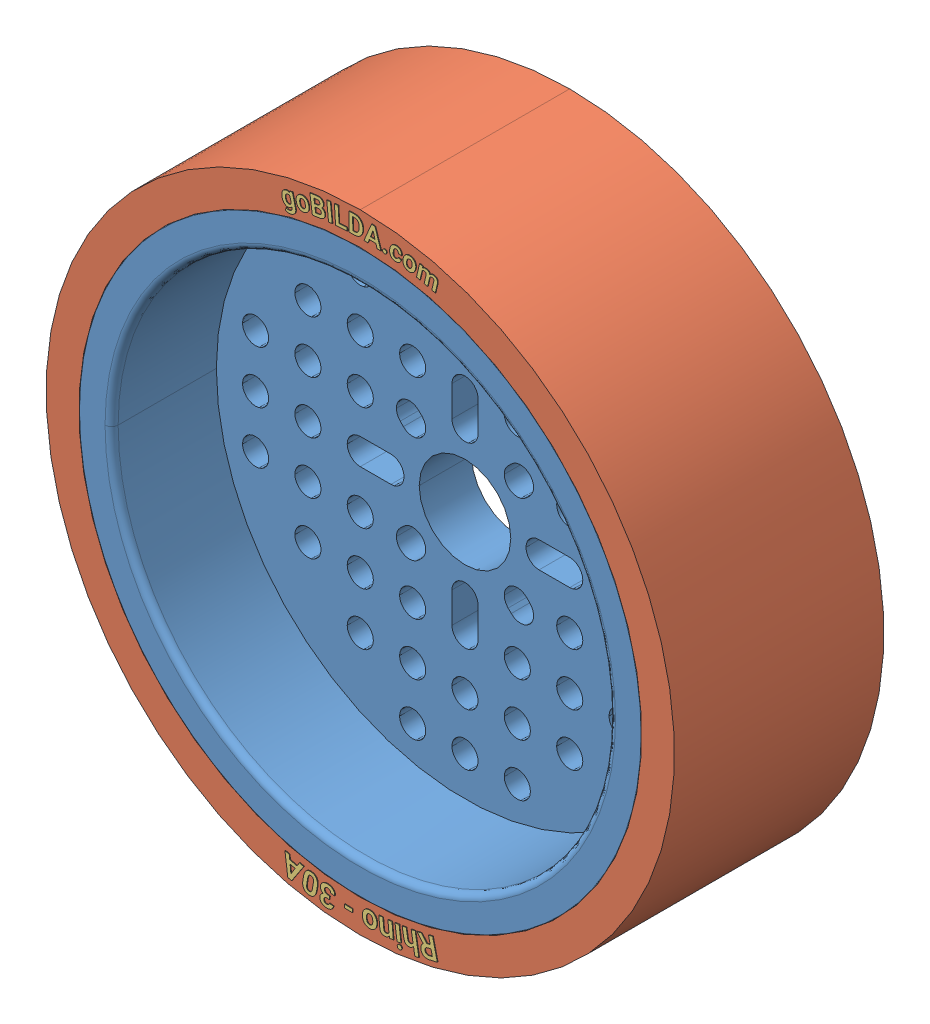
SolidWorks assembly 96mm Rhino Wheel 3614-0014-0096, configuration Default. Lengths in mm.
Overall size (96 96 32.2).
4 component instances, 3 part files, 0 mates.
Components (placement in the parent):
- 3614-0014-0096 wheel.STEP-1: 3614-0014-0096 wheel.STEP [Default] at (-48.1025 19.672 -3.9818) size (86 86 32)
- 3614-0014-0096 wheel ring.STEP-1: 3614-0014-0096 wheel ring.STEP [Default] at (-48.1025 19.672 28.0182) x (1 0 0) z (0 1 0) size (96 32 96)
- 3614-0014-0096 Text.STEP-1: 3614-0014-0096 Text.STEP [Default] at (-161.199 -95.8526 28.0182) size (23.85 93.96 0.1)
- 3614-0014-0096 Text.STEP-2: 3614-0014-0096 Text.STEP [Default] at (-164.2969 132.0802 -3.9818) x (0.999631 0.027177 0) z (0 0 -1) size (23.85 93.96 0.1)
